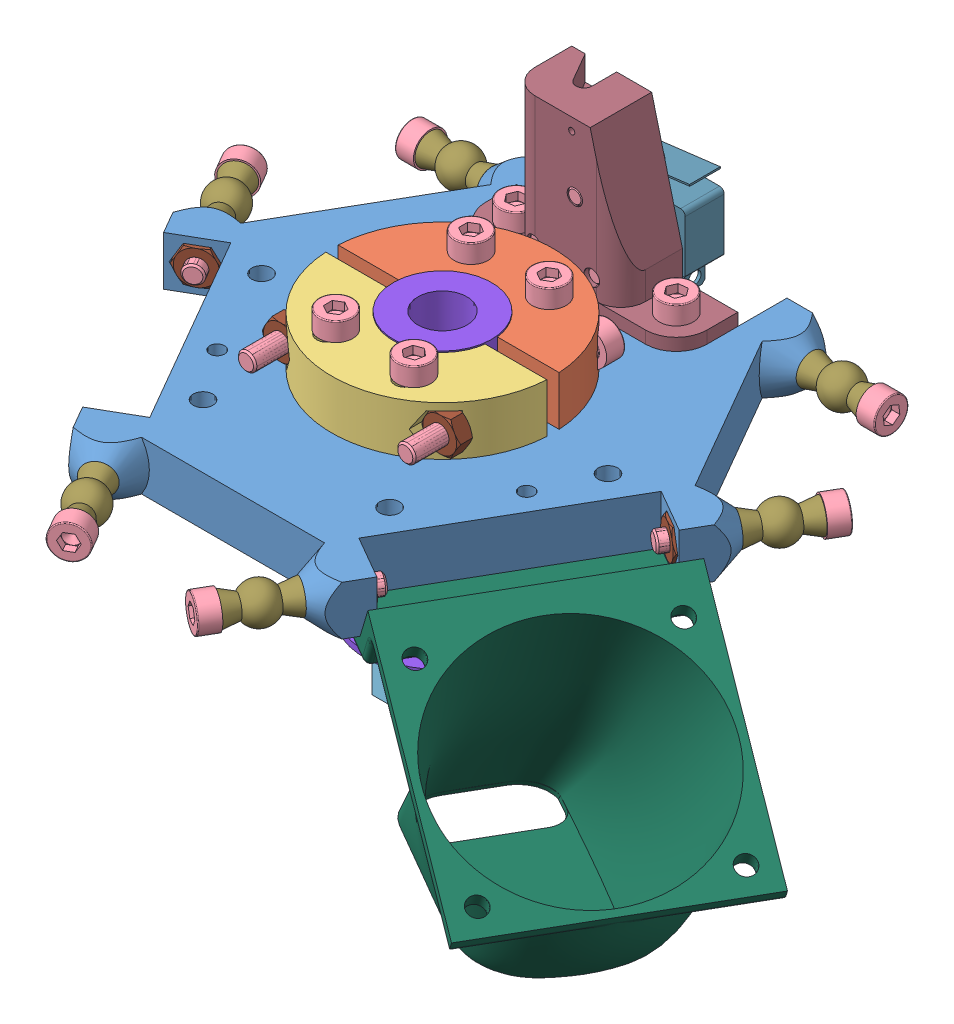
SolidWorks assembly Effector Assy, configuration Default. Lengths in mm.
Overall size (130.76 80.1 96.16).
50 component instances, 15 part files, 107 mates.
Components (placement in the parent):
- Effector-1: Effector [Default] at (2.0411 -5.5405 -1.4674) size (91.07 8 78.8)
- E3D mount part 1-1: E3D mount part 1 [Default] at (2.0411 2.4595 -1.4674) size (35.94 9.5 17)
- E3D mount part 2-1: E3D mount part 2 [Default] at (2.0411 2.4595 -1.4674) x (-1 0 0) z (0 0 -1) size (35.94 9.5 17)
- socket head cap screw_iso-1: socket head cap screw_iso [ISO 4762 M3 x 30 --- 18C] at (-10.9136 6.4595 -15.4674) x (0 0 1) z (-1 0 0) size (33 5.5 5.5)
- socket head cap screw_iso-2: socket head cap screw_iso [ISO 4762 M3 x 30 --- 18C] at (14.9959 6.4595 -15.4674) x (0 0 1) z (-1 0 0) size (33 5.5 5.5)
- E3D-1: E3D [Default] at (2.0411 -45.6405 -6.2174) x (0 0 -1) z (1 0 0) size (28.79 62.3 37.75)
  - E3D Heat Block-1: E3D Heat Block [Default] at origin size (17.5 11.5 16)
  - E3D Heatbreak-1: E3D Heatbreak [Default] at (-4.75 17.5943 0) x (-0.93266 0 -0.360757) z (-0.360757 0 0.93266) size (6 22.19 6)
  - E3D Nozzle-1: E3D Nozzle [Default] at (-4.75 -4 0) x (-0.097107 0 -0.995274) z (0.995274 0 -0.097107) size (8.08 12.5 7)
  - E3D Heatsink-1: E3D Heatsink [1.75 Bowden] at (-4.75 34.95 0) x (0.986263 0 -0.165183) z (0.165183 0 0.986263) size (25 42.7 25)
  - cartridge heater-1: cartridge heater [Default] at (2.25 7 0) x (0 0 1) z (-0.150948 -0.988542 0) size (32 6.2 6.2)
  - thermistor-1: thermistor [Default] at (-6.75 2 6.5) x (-0.997586 0.069447 0) z (-0.069447 -0.997586 0) size (2 13.25 2)
- hex nut style 1 gradeab_iso-1: hex nut style 1 gradeab_iso [Hexagon Nut ISO - 4032 - M3 - D - C] at (14.9959 6.4595 11.9326) x (-0.866025 -0.5 0) z (0 0 1) size (5.5 6.35 2.4)
- hex nut style 1 gradeab_iso-2: hex nut style 1 gradeab_iso [Hexagon Nut ISO - 4032 - M3 - D - C] at (-10.9136 6.4595 11.9326) x (0.866025 0.5 0) z (0 0 1) size (5.5 6.35 2.4)
- Traxxas Ball-1: Traxxas Ball [Default] at (-9.423 -1.5405 46.7206) x (0.75 0.5 -0.433013) z (-0.433013 0.866025 0.25) size (6 10 6)
- Traxxas Ball-2: Traxxas Ball [Default] at (-40.423 -1.5405 -6.973) x (0.75 0.5 -0.433013) z (-0.433013 0.866025 0.25) size (6 10 6)
- Traxxas Ball-3: Traxxas Ball [Default] at (38.0411 -1.5405 -35.4896) x (0 0.5 -0.866025) z (0 0.866025 0.5) size (6 10 6)
- Traxxas Ball-4: Traxxas Ball [Default] at (-23.9589 -1.5405 -35.4896) x (0 0.44145 -0.897286) z (0 0.897286 0.44145) size (6 10 6)
- Traxxas Ball-5: Traxxas Ball [Default] at (44.5052 -1.5405 -6.973) x (0.704825 0.581059 0.406931) z (-0.503212 0.813862 -0.290529) size (6 10 6)
- Traxxas Ball-6: Traxxas Ball [Default] at (13.5052 -1.5405 46.7206) x (0.75 0.5 0.433013) z (-0.433013 0.866025 -0.25) size (6 10 6)
- hex nut style 1 gradeab_iso-4: hex nut style 1 gradeab_iso [Hexagon Nut ISO - 4032 - M3 - D - C] at (-36.223 -1.5405 0.3017) x (0.75 0.5 -0.433013) z (0.5 0 0.866025) size (5.5 6.35 2.4)
- socket head cap screw_iso-3: socket head cap screw_iso [ISO 4762 M3 x 20 --- 20C] at (-46.923 -1.5405 -18.2313) x (0.5 0 0.866025) z (-0.610535 -0.709222 0.352492) size (23 5.5 5.5)
- socket head cap screw_iso-4: socket head cap screw_iso [ISO 4762 M3 x 20 --- 20C] at (-36.9589 -1.5405 -35.4896) x (1 0 0) z (0 -0.709222 0.704985) size (23 5.5 5.5)
- socket head cap screw_iso-5: socket head cap screw_iso [ISO 4762 M3 x 20 --- 20C] at (41.0411 -1.5405 -35.4896) x (-1 0 0) z (0 0.92238 -0.386283) size (23 5.5 5.5)
- socket head cap screw_iso-6: socket head cap screw_iso [ISO 4762 M3 x 20 --- 20C] at (51.0052 -1.5405 -18.2313) x (-0.5 0 0.866025) z (-0.334531 0.92238 -0.193141) size (23 5.5 5.5)
- socket head cap screw_iso-7: socket head cap screw_iso [ISO 4762 M3 x 20 --- 20C] at (12.0052 -1.5405 49.3187) x (0.5 0 -0.866025) z (-0.007901 -0.999958 -0.004561) size (23 5.5 5.5)
- socket head cap screw_iso-8: socket head cap screw_iso [ISO 4762 M3 x 20 --- 20C] at (-7.923 -1.5405 49.3187) x (-0.5 0 -0.866025) z (-0.007901 -0.999958 0.004561) size (23 5.5 5.5)
- hex nut style 1 gradeab_iso-5: hex nut style 1 gradeab_iso [Hexagon Nut ISO - 4032 - M3 - D - C] at (-17.423 -1.5405 32.8642) x (0.75 0.5 -0.433013) z (0.5 0 0.866025) size (5.5 6.35 2.4)
- hex nut style 1 gradeab_iso-6: hex nut style 1 gradeab_iso [Hexagon Nut ISO - 4032 - M3 - D - C] at (21.5052 -1.5405 32.8642) x (-0.75 -0.5 -0.433013) z (-0.5 0 0.866025) size (5.5 6.35 2.4)
- hex nut style 1 gradeab_iso-7: hex nut style 1 gradeab_iso [Hexagon Nut ISO - 4032 - M3 - D - C] at (40.3052 -1.5405 0.3017) x (-0.75 -0.5 -0.433013) z (-0.5 0 0.866025) size (5.5 6.35 2.4)
- hex nut style 1 gradeab_iso-8: hex nut style 1 gradeab_iso [Hexagon Nut ISO - 4032 - M3 - D - C] at (19.6411 -1.5405 -35.4896) x (0 0.5 0.866025) z (-1 0 0) size (5.5 6.35 2.4)
- hex nut style 1 gradeab_iso-9: hex nut style 1 gradeab_iso [Hexagon Nut ISO - 4032 - M3 - D - C] at (-15.5589 -1.5405 -35.4896) x (0 0.5 -0.866025) z (1 0 0) size (5.5 6.35 2.4)
- Level Probe Mount-1: Level Probe Mount [Default] at (20.0411 2.4595 -31.4896) x (-1 0 0) z (0 0 -1) size (36 26 10)
- socket head cap screw_iso-9: socket head cap screw_iso [ISO 4762 M3 x 10 --- 10C] at (15.0411 7.4595 -26.4896) x (0 -1 0) z (-0.92238 0 -0.386283) size (13 5.5 5.5)
- socket head cap screw_iso-10: socket head cap screw_iso [ISO 4762 M3 x 10 --- 10C] at (-10.9589 7.4595 -26.4896) x (0 -1 0) z (-0.92238 0 -0.386283) size (13 5.5 5.5)
- hex nut style 1 gradeab_iso-10: hex nut style 1 gradeab_iso [Hexagon Nut ISO - 4032 - M3 - D - C] at (15.0411 -5.9405 -26.4896) x (-0.866025 0 0.5) z (0 -1 0) size (5.5 6.35 2.4)
- hex nut style 1 gradeab_iso-11: hex nut style 1 gradeab_iso [Hexagon Nut ISO - 4032 - M3 - D - C] at (-10.9589 -5.9405 -26.4896) x (-0.866025 0 0.5) z (0 -1 0) size (5.5 6.35 2.4)
- Micro Switch Button-1: Micro Switch Button [Default] at (0.6911 9.8595 -34.6646) x (0 0 -1) z (1 0 0) size (6.75 16.71 19.86)
- socket head cap screw_iso-11: socket head cap screw_iso [ISO 4762 M2.5 x 16 --- 16C] at (6.2911 7.4595 -40.5396) x (0 0 1) z (-0.842214 0.539143 0) size (18.5 4.5 4.5)
- socket head cap screw_iso-12: socket head cap screw_iso [ISO 4762 M2.5 x 16 --- 16C] at (-3.2089 7.4595 -40.5396) x (0 0 1) z (-0.842214 0.539143 0) size (18.5 4.5 4.5)
- socket head cap screw_iso-13: socket head cap screw_iso [ISO 4762 M2.5 x 10 --- 10C] at (3.5411 17.4595 -33.9896) x (0 0 1) z (-0.842214 0.539143 0) size (12.5 4.5 4.5)
- socket head cap screw_iso-14: socket head cap screw_iso [ISO 4762 M3 x 16 --- 16C] at (-4.3097 13.4595 -12.4674) x (0 -1 0) z (-1 0 0) size (19 5.5 5.5)
- hex nut style 1 gradeab_iso-12: hex nut style 1 gradeab_iso [Hexagon Nut ISO - 4032 - M3 - D - C] at (-4.3097 -5.9405 -12.4674) x (-0.866025 0 0.5) z (0 -1 0) size (5.5 6.35 2.4)
- socket head cap screw_iso-15: socket head cap screw_iso [ISO 4762 M3 x 16 --- 16C] at (8.392 13.4595 -12.4674) x (0 -1 0) z (-1 0 0) size (19 5.5 5.5)
- socket head cap screw_iso-16: socket head cap screw_iso [ISO 4762 M3 x 16 --- 16C] at (-4.3097 13.4595 9.5326) x (0 -1 0) z (-0.512365 0 -0.858768) size (19 5.5 5.5)
- socket head cap screw_iso-17: socket head cap screw_iso [ISO 4762 M3 x 16 --- 16C] at (8.392 13.4595 9.5326) x (0 -1 0) z (-0.340777 0 -0.940144) size (19 5.5 5.5)
- hex nut style 1 gradeab_iso-13: hex nut style 1 gradeab_iso [Hexagon Nut ISO - 4032 - M3 - D - C] at (8.392 -5.9405 9.5326) x (-0.866025 0 -0.5) z (0 -1 0) size (5.5 6.35 2.4)
- hex nut style 1 gradeab_iso-14: hex nut style 1 gradeab_iso [Hexagon Nut ISO - 4032 - M3 - D - C] at (-4.3097 -5.9405 9.5326) x (-0.866025 0 -0.5) z (0 -1 0) size (5.5 6.35 2.4)
- hex nut style 1 gradeab_iso-15: hex nut style 1 gradeab_iso [Hexagon Nut ISO - 4032 - M3 - D - C] at (8.392 -5.9405 -12.4674) x (-0.866025 0 0.5) z (0 -1 0) size (5.5 6.35 2.4)
- Fan Duct-1: Fan Duct [Default] at (11.2861 -5.5405 26.9642) x (0.5 0 -0.866025) z (0.866025 0 0.5) size (40.89 48.01 66.54)
Mates (geometry in assembly coordinates):
- Concentric1: concentric aligned: cylinder of Effector-1 through (8.392 2.4595 -12.4674) axis (0 -1 0) radius 1.6; cylinder of E3D mount part 1-1 through (8.392 10.4595 -12.4674) axis (0 -1 0) radius 1.6
- Concentric2: concentric aligned: cylinder of Effector-1 through (-4.3097 2.4595 -12.4674) axis (0 -1 0) radius 1.6; cylinder of E3D mount part 1-1 through (-4.3097 10.4595 -12.4674) axis (0 -1 0) radius 1.6
- Coincident1: coincident anti-aligned: plane of Effector-1 through (2.0411 2.4595 -1.4674) normal (0 1 0); plane of E3D mount part 1-1 through (2.0411 2.4595 -1.4674) normal (0 -1 0)
- Parallel1: parallel anti-aligned: plane of E3D mount part 1-1 through (-17.9589 0.9595 -2.4674) normal (0 0 1); plane of E3D mount part 2-1 through (22.0411 0.9595 -0.4674) normal (0 0 -1)
- Concentric3: concentric anti-aligned: cylinder of E3D mount part 1-1 through (14.9959 6.4595 -19.4684) axis (0 0 1) radius 1.6; cylinder of E3D mount part 2-1 through (14.9959 6.4595 16.5336) axis (0 0 -1) radius 1.6
- Concentric4: concentric anti-aligned: cylinder of E3D mount part 1-1 through (-10.9136 6.4595 -19.4684) axis (0 0 1) radius 1.6; cylinder of E3D mount part 2-1 through (-10.9136 6.4595 16.5336) axis (0 0 -1) radius 1.6
- Concentric5: concentric aligned: cylinder of Effector-1 through (2.0411 2.4595 -1.4674) axis (0 -1 0) radius 8; cylinder of E3D mount part 2-1 through (2.0411 10.4595 -1.4674) axis (0 -1 0) radius 8
- Concentric6: concentric anti-aligned: cylinder of E3D mount part 1-1 through (-10.9136 6.4595 -19.4684) axis (0 0 1) radius 1.6; cylinder of socket head cap screw_iso-1 through (-10.9136 6.4595 -47.2174) axis (0 0 -1) radius 1.5
- Coincident3: coincident anti-aligned: plane of E3D mount part 1-1 through (-10.9136 6.4595 -12.4674) normal (0 0 -1); plane of socket head cap screw_iso-1 through (-10.9136 9.2095 -12.4674) normal (0 0 1)
- Concentric71: concentric anti-aligned: cylinder of E3D mount part 1-1 through (14.9959 6.4595 -19.4684) axis (0 0 1) radius 1.6; cylinder of socket head cap screw_iso-2 through (14.9959 6.4595 -47.2174) axis (0 0 -1) radius 2.75
- Coincident41: coincident anti-aligned: plane of E3D mount part 1-1 through (14.9959 6.4595 -12.4674) normal (0 0 -1); plane of socket head cap screw_iso-2 through (14.9959 9.2095 -12.4674) normal (0 0 1)
- Concentric10: concentric anti-aligned: cylinder of E3D mount part 1-1 through (2.0411 0.9595 -1.4674) axis (0 1 0) radius 6; cylinder of E3D-1/E3D Heatsink-1 through (2.0411 -32.0405 -1.4674) axis (0 -1 0) radius 6
- Coincident9: coincident anti-aligned: plane of E3D mount part 1-1 through (2.0411 0.9595 -1.4674) normal (0 -1 0); plane of E3D-1/E3D Heatsink-1 through (0.7197 0.9595 -9.3575) normal (0 1 0)
- Parallel4: parallel aligned: plane of Effector-1 through (-19.9589 2.4595 -31.4896) normal (0 0 -1); plane of E3D-1/E3D Heat Block-1 through (10.0411 -34.1405 -14.9674) normal (0 0 -1)
- Concentric11: concentric anti-aligned: cylinder of socket head cap screw_iso-2 through (14.9959 6.4595 -47.2174) axis (0 0 -1) radius 1.5; cylinder of hex nut style 1 gradeab_iso-1 through (14.9959 6.4595 9.5326) axis (0 0 1) radius 1.25
- Parallel5: parallel anti-aligned: plane of E3D mount part 2-1 through (16.6124 3.6595 16.5336) normal (0 1 0); plane of hex nut style 1 gradeab_iso-1 through (13.4082 3.7095 9.5326) normal (0 -1 0)
- Coincident12: coincident anti-aligned: plane of E3D mount part 2-1 through (2.0411 2.4595 9.5326) normal (0 0 1); plane of hex nut style 1 gradeab_iso-1 through (16.5836 3.7095 9.5326) normal (0 0 -1)
- Concentric12: concentric anti-aligned: cylinder of socket head cap screw_iso-1 through (-10.9136 6.4595 -47.2174) axis (0 0 -1) radius 1.5; cylinder of hex nut style 1 gradeab_iso-2 through (-10.9136 6.4595 9.5326) axis (0 0 1) radius 1.25
- Parallel6: parallel anti-aligned: plane of E3D mount part 2-1 through (-9.297 3.6595 16.5336) normal (0 1 0); plane of hex nut style 1 gradeab_iso-2 through (-12.5013 3.7095 9.5326) normal (0 -1 0)
- Coincident14: coincident anti-aligned: plane of E3D mount part 2-1 through (2.0411 2.4595 9.5326) normal (0 0 1); plane of hex nut style 1 gradeab_iso-2 through (-12.5013 9.2095 9.5326) normal (0 0 -1)
- Coincident15: coincident anti-aligned: plane of Effector-1 through (-5.7627 -5.5405 33.0604) normal (0.5 0 0.866025); plane of Traxxas Ball-1 through (-13.298 -0.7905 37.4108) normal (-0.5 0 -0.866025)
- Concentric13: concentric aligned: cylinder of Effector-1 through (-42.5443 -1.5405 -10.6472) axis (0.5 0 0.866025) radius 1.5; cylinder of Traxxas Ball-1 through (-9.423 -1.5405 46.7206) axis (0.5 0 0.866025) radius 1.5
- Coincident16: coincident anti-aligned: plane of Effector-1 through (-31.7627 2.4595 -11.973) normal (-0.5 0 -0.866025); plane of Traxxas Ball-2 through (-38.548 -0.2905 -8.0555) normal (0.5 0 0.866025)
- Concentric14: concentric aligned: cylinder of Effector-1 through (-42.5443 -1.5405 -10.6472) axis (0.5 0 0.866025) radius 1.5; cylinder of Traxxas Ball-2 through (-40.423 -1.5405 -6.973) axis (0.5 0 0.866025) radius 1.5
- Concentric17: concentric anti-aligned: cylinder of Effector-1 through (32.2838 -1.5405 -35.4896) axis (-1 0 0) radius 1.5; cylinder of Traxxas Ball-4 through (-23.9589 -1.5405 -35.4896) axis (1 0 0) radius 1.5
- Coincident17: coincident anti-aligned: plane of Effector-1 through (-23.9589 -5.5405 -25.4896) normal (-1 0 0); plane of Traxxas Ball-4 through (-23.9589 -0.4368 -37.7328) normal (1 0 0)
- Coincident18: coincident anti-aligned: plane of Effector-1 through (28.0411 2.4595 -25.4896) normal (1 0 0); plane of Traxxas Ball-3 through (28.0411 -0.7905 -36.7887) normal (-1 0 0)
- Concentric18: concentric anti-aligned: cylinder of Traxxas Ball-3 through (38.0411 -1.5405 -35.4896) axis (1 0 0) radius 1.5; cylinder of Effector-1 through (32.2838 -1.5405 -35.4896) axis (-1 0 0) radius 1.5
- Concentric19: concentric anti-aligned: cylinder of Effector-1 through (16.3839 -1.5405 41.7346) axis (0.5 0 -0.866025) radius 1.5; cylinder of Traxxas Ball-5 through (44.5052 -1.5405 -6.973) axis (-0.5 0 0.866025) radius 1.5
- Coincident19: coincident anti-aligned: plane of Effector-1 through (35.845 -5.5405 -11.973) normal (0.5 0 -0.866025); plane of Traxxas Ball-5 through (46.2673 -0.0878 -5.9556) normal (-0.5 0 0.866025)
- Coincident20: coincident anti-aligned: plane of Effector-1 through (9.845 2.4595 33.0604) normal (-0.5 0 0.866025); plane of Traxxas Ball-6 through (19.6302 -0.7905 38.7099) normal (0.5 0 -0.866025)
- Concentric21: concentric anti-aligned: cylinder of Effector-1 through (16.3839 -1.5405 41.7346) axis (0.5 0 -0.866025) radius 1.5; cylinder of Traxxas Ball-6 through (13.5052 -1.5405 46.7206) axis (-0.5 0 0.866025) radius 1.5
- Concentric22: concentric anti-aligned: cylinder of Effector-1 through (-42.5443 -1.5405 -10.6472) axis (0.5 0 0.866025) radius 1.5; cylinder of socket head cap screw_iso-3 through (-62.798 -1.5405 -45.7276) axis (-0.5 0 -0.866025) radius 1.5
- Coincident21: coincident anti-aligned: plane of Traxxas Ball-2 through (-44.298 -0.7905 -16.2827) normal (-0.5 0 -0.866025); plane of socket head cap screw_iso-3 through (-47.112 0.3982 -14.658) normal (0.5 0 0.866025)
- Concentric23: concentric anti-aligned: cylinder of hex nut style 1 gradeab_iso-4 through (-37.423 -1.5405 -1.7768) axis (0.5 0 0.866025) radius 1.25; cylinder of socket head cap screw_iso-3 through (-62.798 -1.5405 -45.7276) axis (-0.5 0 -0.866025) radius 1.5
- Parallel8: parallel: plane of hex nut style 1 gradeab_iso-4 through (-36.048 1.2095 -2.5707) normal (0 1 0); line of Effector-1 through (-37.873 1.3595 0.7924) axis (0.866025 0 -0.5)
- Coincident23: coincident anti-aligned: plane of Effector-1 through (-7.9589 -5.5405 -18.7879) normal (0.5 0 0.866025); plane of hex nut style 1 gradeab_iso-4 through (-38.798 1.2095 -0.983) normal (-0.5 0 -0.866025)
- Concentric241: concentric anti-aligned: cylinder of Traxxas Ball-4 through (-23.9589 -1.5405 -35.4896) axis (1 0 0) radius 1.5; cylinder of socket head cap screw_iso-4 through (-68.7089 -1.5405 -35.4896) axis (-1 0 0) radius 2.75
- Coincident241: coincident anti-aligned: plane of Traxxas Ball-4 through (-33.9589 -0.8783 -36.8355) normal (-1 0 0); plane of socket head cap screw_iso-4 through (-33.9589 0.3982 -33.5393) normal (1 0 0)
- Concentric251: concentric aligned: cylinder of Traxxas Ball-3 through (38.0411 -1.5405 -35.4896) axis (1 0 0) radius 1.5; cylinder of socket head cap screw_iso-5 through (72.7911 -1.5405 -35.4896) axis (1 0 0) radius 2.75
- Coincident251: coincident anti-aligned: plane of Traxxas Ball-3 through (38.0411 -0.2905 -37.6547) normal (1 0 0); plane of socket head cap screw_iso-5 through (38.0411 -0.4782 -32.9531) normal (-1 0 0)
- Concentric261: concentric anti-aligned: cylinder of Traxxas Ball-5 through (44.5052 -1.5405 -6.973) axis (-0.5 0 0.866025) radius 1.5; cylinder of socket head cap screw_iso-6 through (66.8802 -1.5405 -45.7276) axis (0.5 0 -0.866025) radius 2.75
- Coincident261: coincident anti-aligned: plane of Traxxas Ball-5 through (50.5625 -0.6689 -15.0228) normal (0.5 0 -0.866025); plane of socket head cap screw_iso-6 through (51.702 -0.4782 -14.3649) normal (-0.5 0 0.866025)
- Concentric271: concentric aligned: cylinder of Traxxas Ball-6 through (13.5052 -1.5405 46.7206) axis (-0.5 0 0.866025) radius 1.5; cylinder of socket head cap screw_iso-7 through (-3.8698 -1.5405 76.815) axis (-0.5 0 0.866025) radius 2.75
- Coincident271: coincident anti-aligned: plane of Traxxas Ball-6 through (15.3802 -0.2905 47.8031) normal (-0.5 0 0.866025); plane of socket head cap screw_iso-7 through (15.8867 -1.5656 48.0956) normal (0.5 0 -0.866025)
- Concentric281: concentric aligned: cylinder of Traxxas Ball-1 through (-9.423 -1.5405 46.7206) axis (0.5 0 0.866025) radius 1.5; cylinder of socket head cap screw_iso-8 through (7.952 -1.5405 76.815) axis (0.5 0 0.866025) radius 2.75
- Coincident281: coincident anti-aligned: plane of Traxxas Ball-1 through (-7.548 -0.2905 45.6381) normal (0.5 0 0.866025); plane of socket head cap screw_iso-8 through (-7.0415 -1.5656 45.3457) normal (-0.5 0 -0.866025)
- Concentric29: concentric aligned: cylinder of socket head cap screw_iso-8 through (7.952 -1.5405 76.815) axis (0.5 0 0.866025) radius 1.5; cylinder of hex nut style 1 gradeab_iso-5 through (-18.623 -1.5405 30.7857) axis (0.5 0 0.866025) radius 1.25
- Parallel9: parallel: line of Effector-1 through (-19.873 1.3595 31.9693) axis (0.866025 0 -0.5); plane of hex nut style 1 gradeab_iso-5 through (-17.248 1.2095 29.9919) normal (0 1 0)
- Coincident30: coincident anti-aligned: plane of Effector-1 through (12.0411 -5.5405 15.8531) normal (-0.5 0 -0.866025); plane of hex nut style 1 gradeab_iso-5 through (-18.798 1.2095 33.6581) normal (0.5 0 0.866025)
- Concentric30: concentric aligned: cylinder of socket head cap screw_iso-7 through (-3.8698 -1.5405 76.815) axis (-0.5 0 0.866025) radius 1.5; cylinder of hex nut style 1 gradeab_iso-6 through (22.7052 -1.5405 30.7857) axis (-0.5 0 0.866025) radius 1.25
- Concentric31: concentric anti-aligned: cylinder of socket head cap screw_iso-6 through (66.8802 -1.5405 -45.7276) axis (0.5 0 -0.866025) radius 1.5; cylinder of hex nut style 1 gradeab_iso-7 through (41.5052 -1.5405 -1.7768) axis (-0.5 0 0.866025) radius 1.25
- Concentric32: concentric anti-aligned: cylinder of socket head cap screw_iso-5 through (72.7911 -1.5405 -35.4896) axis (1 0 0) radius 1.5; cylinder of hex nut style 1 gradeab_iso-8 through (22.0411 -1.5405 -35.4896) axis (-1 0 0) radius 1.25
- Concentric33: concentric anti-aligned: cylinder of socket head cap screw_iso-4 through (-68.7089 -1.5405 -35.4896) axis (-1 0 0) radius 1.5; cylinder of hex nut style 1 gradeab_iso-9 through (-17.9589 -1.5405 -35.4896) axis (1 0 0) radius 1.25
- Parallel10: parallel: line of Effector-1 through (23.9552 1.3595 31.9693) axis (-0.866025 0 -0.5); plane of hex nut style 1 gradeab_iso-6 through (24.0802 1.2095 31.5796) normal (0 1 0)
- Coincident32: coincident anti-aligned: plane of Effector-1 through (-7.9589 -5.5405 15.8531) normal (0.5 0 -0.866025); plane of hex nut style 1 gradeab_iso-6 through (22.8802 -4.2905 33.6581) normal (-0.5 0 0.866025)
- Parallel11: parallel: line of Effector-1 through (41.9552 1.3595 0.7924) axis (-0.866025 0 -0.5); plane of hex nut style 1 gradeab_iso-7 through (42.8802 1.2095 -0.983) normal (0 1 0)
- Coincident34: coincident anti-aligned: plane of Effector-1 through (12.0411 -5.5405 -18.7879) normal (-0.5 0 0.866025); plane of hex nut style 1 gradeab_iso-7 through (42.8802 -4.2905 -0.983) normal (0.5 0 -0.866025)
- Parallel12: parallel: line of Effector-1 through (20.0411 1.3595 -37.1639) axis (0 0 1); plane of hex nut style 1 gradeab_iso-8 through (22.0411 1.2095 -33.9019) normal (0 1 0)
- Coincident36: coincident anti-aligned: plane of Effector-1 through (22.0411 -5.5405 -1.4674) normal (-1 0 0); plane of hex nut style 1 gradeab_iso-8 through (22.0411 1.2095 -37.0773) normal (1 0 0)
- Parallel13: parallel: line of Effector-1 through (-15.9589 1.3595 -37.1639) axis (0 0 1); plane of hex nut style 1 gradeab_iso-9 through (-17.9589 1.2095 -37.0773) normal (0 1 0)
- Coincident38: coincident anti-aligned: plane of Effector-1 through (-17.9589 -5.5405 -1.4674) normal (1 0 0); plane of hex nut style 1 gradeab_iso-9 through (-17.9589 1.2095 -33.9019) normal (-1 0 0)
- Coincident46: coincident aligned: plane of Effector-1 through (-19.9589 2.4595 -31.4896) normal (0 0 -1); plane of Level Probe Mount-1 through (20.0411 4.4595 -31.4896) normal (0 0 -1)
- Coincident47: coincident anti-aligned: plane of Effector-1 through (2.0411 2.4595 -1.4674) normal (0 1 0); plane of Level Probe Mount-1 through (15.0411 2.4595 -26.4896) normal (0 -1 0)
- Concentric341: concentric anti-aligned: cylinder of Level Probe Mount-1 through (15.0411 4.4595 -26.4896) axis (0 -1 0) radius 1.6; cylinder of socket head cap screw_iso-9 through (15.0411 39.2095 -26.4896) axis (0 1 0) radius 2.75
- Coincident481: coincident anti-aligned: plane of Level Probe Mount-1 through (15.0411 4.4595 -26.4896) normal (0 1 0); plane of socket head cap screw_iso-9 through (13.9789 4.4595 -23.9531) normal (0 -1 0)
- Concentric351: concentric anti-aligned: cylinder of Level Probe Mount-1 through (-10.9589 4.4595 -26.4896) axis (0 -1 0) radius 1.6; cylinder of socket head cap screw_iso-10 through (-10.9589 39.2095 -26.4896) axis (0 1 0) radius 2.75
- Coincident491: coincident anti-aligned: plane of Level Probe Mount-1 through (15.0411 4.4595 -26.4896) normal (0 1 0); plane of socket head cap screw_iso-10 through (-12.0211 4.4595 -23.9531) normal (0 -1 0)
- Concentric36: concentric anti-aligned: cylinder of socket head cap screw_iso-9 through (15.0411 39.2095 -26.4896) axis (0 1 0) radius 1.5; cylinder of hex nut style 1 gradeab_iso-10 through (15.0411 -3.5405 -26.4896) axis (0 -1 0) radius 1.25
- Parallel16: parallel: line of Effector-1 through (13.4246 -5.5405 -29.2896) axis (1 0 0); plane of hex nut style 1 gradeab_iso-10 through (13.4534 -3.5405 -29.2396) normal (0 0 -1)
- Coincident51: coincident anti-aligned: plane of Effector-1 through (2.0411 -3.5405 -1.4674) normal (0 -1 0); plane of hex nut style 1 gradeab_iso-10 through (13.4534 -3.5405 -29.2396) normal (0 1 0)
- Concentric37: concentric anti-aligned: cylinder of socket head cap screw_iso-10 through (-10.9589 39.2095 -26.4896) axis (0 1 0) radius 1.5; cylinder of hex nut style 1 gradeab_iso-11 through (-10.9589 -3.5405 -26.4896) axis (0 -1 0) radius 1.25
- Parallel17: parallel: line of Effector-1 through (-12.5754 -5.5405 -29.2896) axis (1 0 0); plane of hex nut style 1 gradeab_iso-11 through (-12.5466 -3.5405 -29.2396) normal (0 0 -1)
- Coincident53: coincident anti-aligned: plane of Effector-1 through (2.0411 -3.5405 -1.4674) normal (0 -1 0); plane of hex nut style 1 gradeab_iso-11 through (-12.5466 -3.5405 -29.2396) normal (0 1 0)
- Concentric38: concentric aligned: cylinder of Level Probe Mount-1 through (6.2911 7.4595 -21.4886) axis (0 0 -1) radius 1.25; cylinder of Micro Switch Button-1 through (6.2911 7.4595 -31.4896) axis (0 0 -1) radius 1.35
- Concentric39: concentric aligned: cylinder of Level Probe Mount-1 through (-3.2089 7.4595 -21.4886) axis (0 0 -1) radius 1.25; cylinder of Micro Switch Button-1 through (-3.2089 7.4595 -31.4896) axis (0 0 -1) radius 1.35
- Coincident54: coincident anti-aligned: plane of Level Probe Mount-1 through (20.0411 4.4595 -31.4896) normal (0 0 -1); plane of Micro Switch Button-1 through (-8.1089 5.2595 -31.4896) normal (0 0 1)
- Concentric40: concentric aligned: cylinder of Level Probe Mount-1 through (6.2911 7.4595 -21.4886) axis (0 0 -1) radius 1.25; cylinder of socket head cap screw_iso-11 through (6.2911 7.4595 -72.2896) axis (0 0 -1) radius 1.25
- Concentric41: concentric anti-aligned: cylinder of Effector-1 through (-10.9589 2.4595 -26.4896) axis (0 -1 0) radius 1.6; cylinder of socket head cap screw_iso-10 through (-10.9589 39.2095 -26.4896) axis (0 1 0) radius 1.5
- Coincident55: coincident anti-aligned: plane of Micro Switch Button-1 through (6.2911 7.4595 -38.0396) normal (0 0 -1); plane of socket head cap screw_iso-11 through (7.5042 9.3545 -38.0396) normal (0 0 1)
- Concentric421: concentric aligned: cylinder of Micro Switch Button-1 through (-3.2089 7.4595 -31.4896) axis (0 0 -1) radius 1.35; cylinder of socket head cap screw_iso-12 through (-3.2089 7.4595 -72.2896) axis (0 0 -1) radius 2.25
- Coincident561: coincident anti-aligned: plane of Micro Switch Button-1 through (-3.2089 7.4595 -38.0396) normal (0 0 -1); plane of socket head cap screw_iso-12 through (-1.9958 9.3545 -38.0396) normal (0 0 1)
- Concentric431: concentric aligned: cylinder of Level Probe Mount-1 through (3.5411 17.4595 -21.4886) axis (0 0 -1) radius 1.25; cylinder of socket head cap screw_iso-13 through (3.5411 17.4595 -65.7396) axis (0 0 -1) radius 2.25
- Coincident571: coincident anti-aligned: plane of Level Probe Mount-1 through (20.0411 4.4595 -31.4896) normal (0 0 -1); plane of socket head cap screw_iso-13 through (4.7542 19.3545 -31.4896) normal (0 0 1)
- Concentric44: concentric anti-aligned: cylinder of E3D mount part 1-1 through (-4.3097 10.4595 -12.4674) axis (0 -1 0) radius 1.6; cylinder of socket head cap screw_iso-14 through (-4.3097 45.2095 -12.4674) axis (0 1 0) radius 1.5
- Coincident58: coincident anti-aligned: plane of E3D mount part 1-1 through (2.0411 10.4595 -1.4674) normal (0 1 0); plane of socket head cap screw_iso-14 through (-4.3097 10.4595 -9.7174) normal (0 -1 0)
- Concentric45: concentric anti-aligned: cylinder of socket head cap screw_iso-14 through (-4.3097 45.2095 -12.4674) axis (0 1 0) radius 1.5; cylinder of hex nut style 1 gradeab_iso-12 through (-4.3097 -3.5405 -12.4674) axis (0 -1 0) radius 1.25
- Parallel18: parallel: line of Effector-1 through (-2.6931 -5.5405 -15.2674) axis (0.5 0 0.866025); plane of hex nut style 1 gradeab_iso-12 through (-2.722 -3.5405 -15.2174) normal (0.866025 0 -0.5)
- Coincident60: coincident anti-aligned: plane of Effector-1 through (2.0411 -3.5405 -1.4674) normal (0 -1 0); plane of hex nut style 1 gradeab_iso-12 through (-5.8974 -3.5405 -15.2174) normal (0 1 0)
- Concentric461: concentric anti-aligned: cylinder of E3D mount part 1-1 through (8.392 10.4595 -12.4674) axis (0 -1 0) radius 1.6; cylinder of socket head cap screw_iso-15 through (8.392 45.2095 -12.4674) axis (0 1 0) radius 2.75
- Coincident611: coincident anti-aligned: plane of E3D mount part 1-1 through (2.0411 10.4595 -1.4674) normal (0 1 0); plane of socket head cap screw_iso-15 through (8.392 10.4595 -9.7174) normal (0 -1 0)
- Concentric47: concentric anti-aligned: cylinder of Effector-1 through (-4.3097 2.4595 9.5326) axis (0 -1 0) radius 1.6; cylinder of socket head cap screw_iso-16 through (-4.3097 45.2095 9.5326) axis (0 1 0) radius 1.5
- Concentric48: concentric anti-aligned: cylinder of Effector-1 through (8.392 2.4595 9.5326) axis (0 -1 0) radius 1.6; cylinder of socket head cap screw_iso-17 through (8.392 45.2095 9.5326) axis (0 1 0) radius 1.5
- Concentric49: concentric anti-aligned: cylinder of socket head cap screw_iso-16 through (-4.3097 45.2095 9.5326) axis (0 1 0) radius 1.5; cylinder of hex nut style 1 gradeab_iso-14 through (-4.3097 -3.5405 9.5326) axis (0 -1 0) radius 1.25
- Concentric50: concentric anti-aligned: cylinder of socket head cap screw_iso-17 through (8.392 45.2095 9.5326) axis (0 1 0) radius 1.5; cylinder of hex nut style 1 gradeab_iso-13 through (8.392 -3.5405 9.5326) axis (0 -1 0) radius 1.25
- Parallel19: parallel aligned: plane of Effector-1 through (-5.9263 -3.5405 6.7326) normal (0 0 1); plane of hex nut style 1 gradeab_iso-14 through (-2.722 -3.5405 12.2826) normal (0 0 1)
- Coincident63: coincident anti-aligned: plane of Effector-1 through (2.0411 -3.5405 -1.4674) normal (0 -1 0); plane of hex nut style 1 gradeab_iso-14 through (-2.722 -3.5405 6.7826) normal (0 1 0)
- Parallel20: parallel: line of Effector-1 through (10.0086 -5.5405 12.3326) axis (-1 0 0); plane of hex nut style 1 gradeab_iso-13 through (9.9797 -3.5405 12.2826) normal (0 0 1)
- Coincident65: coincident anti-aligned: plane of Effector-1 through (2.0411 -3.5405 -1.4674) normal (0 -1 0); plane of hex nut style 1 gradeab_iso-13 through (9.9797 -3.5405 6.7826) normal (0 1 0)
- Coincident66: coincident anti-aligned: plane of E3D mount part 2-1 through (2.0411 10.4595 -1.4674) normal (0 1 0); plane of socket head cap screw_iso-16 through (-6.6713 10.4595 10.9416) normal (0 -1 0)
- Coincident67: coincident anti-aligned: plane of E3D mount part 2-1 through (2.0411 10.4595 -1.4674) normal (0 1 0); plane of socket head cap screw_iso-17 through (5.8066 10.4595 10.4697) normal (0 -1 0)
- Parallel21: parallel: line of Effector-1 through (10.0086 -5.5405 -15.2674) axis (0.5 0 0.866025); plane of hex nut style 1 gradeab_iso-15 through (9.9797 -3.5405 -15.2174) normal (0.866025 0 -0.5)
- Concentric51: concentric anti-aligned: cylinder of socket head cap screw_iso-15 through (8.392 45.2095 -12.4674) axis (0 1 0) radius 1.5; cylinder of hex nut style 1 gradeab_iso-15 through (8.392 -3.5405 -12.4674) axis (0 -1 0) radius 1.25
- Coincident69: coincident anti-aligned: plane of Effector-1 through (2.0411 -3.5405 -1.4674) normal (0 -1 0); plane of hex nut style 1 gradeab_iso-15 through (6.8043 -3.5405 -15.2174) normal (0 1 0)
- Concentric462: concentric anti-aligned: cylinder of Effector-1 through (17.211 2.4595 22.302) axis (0 -1 0) radius 1.6; cylinder of Fan Duct-1 through (17.211 -23.1565 22.302) axis (0 1 0) radius 1.5
- Concentric463: concentric anti-aligned: cylinder of Effector-1 through (30.211 2.4595 -0.2146) axis (0 -1 0) radius 1.6; cylinder of Fan Duct-1 through (30.211 -23.1565 -0.2146) axis (0 1 0) radius 1.5
- Coincident612: coincident anti-aligned: plane of Effector-1 through (2.0411 -5.5405 -1.4674) normal (0 -1 0); plane of Fan Duct-1 through (31.2861 -5.5405 -7.6768) normal (0 1 0)
